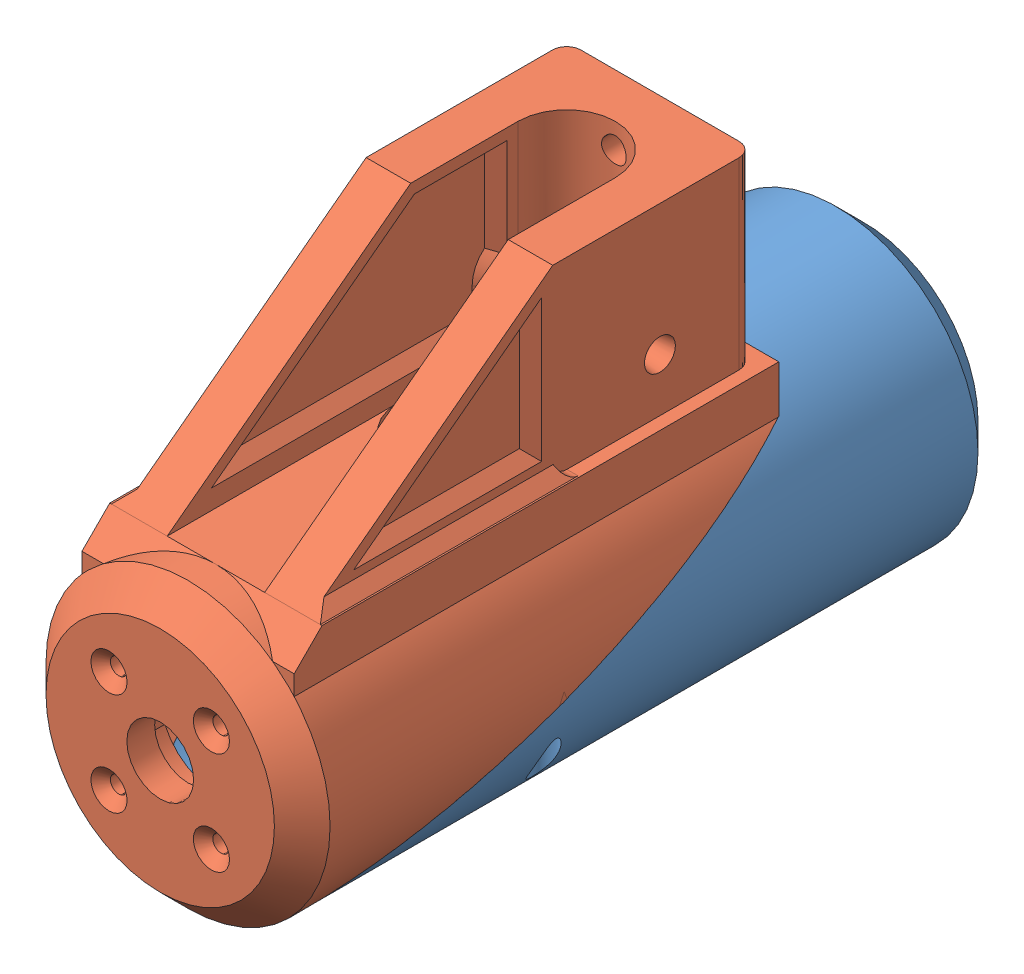
SolidWorks assembly drive_motor_mount, configuration Default. Lengths in mm.
Overall size (51 84 126.3).
2 component instances, 2 part files, 3 mates.
Components (placement in the parent):
- drive_motor_cap-1: drive_motor_cap [Default] at (-110.811 0.8337 -2.0179) size (51 51 116.5)
- drive_motor_mount_v2-1: drive_motor_mount_v2 [Default] at (-110.811 0.8337 124.2821) x (-1 0 0) z (0 0 -1) size (51 84 92)
Mates (geometry in assembly coordinates):
- Coincident1: coincident anti-aligned: plane of drive_motor_cap-1 through (-85.311 17.8337 32.2821) normal (0 0 1); plane of drive_motor_mount_v2-1 through (-110.811 0.8337 32.2821) normal (0 0 -1)
- Concentric1: concentric anti-aligned: cylinder of drive_motor_cap-1 through (-110.811 0.8337 122.9821) axis (0 0 -1) radius 25.5; cylinder of drive_motor_mount_v2-1 through (-110.811 0.8337 32.2821) axis (0 0 1) radius 25.5
- Coincident2: coincident aligned: plane of drive_motor_cap-1 through (-110.811 0.8337 -2.0179) normal (0 1 0); plane of drive_motor_mount_v2-1
